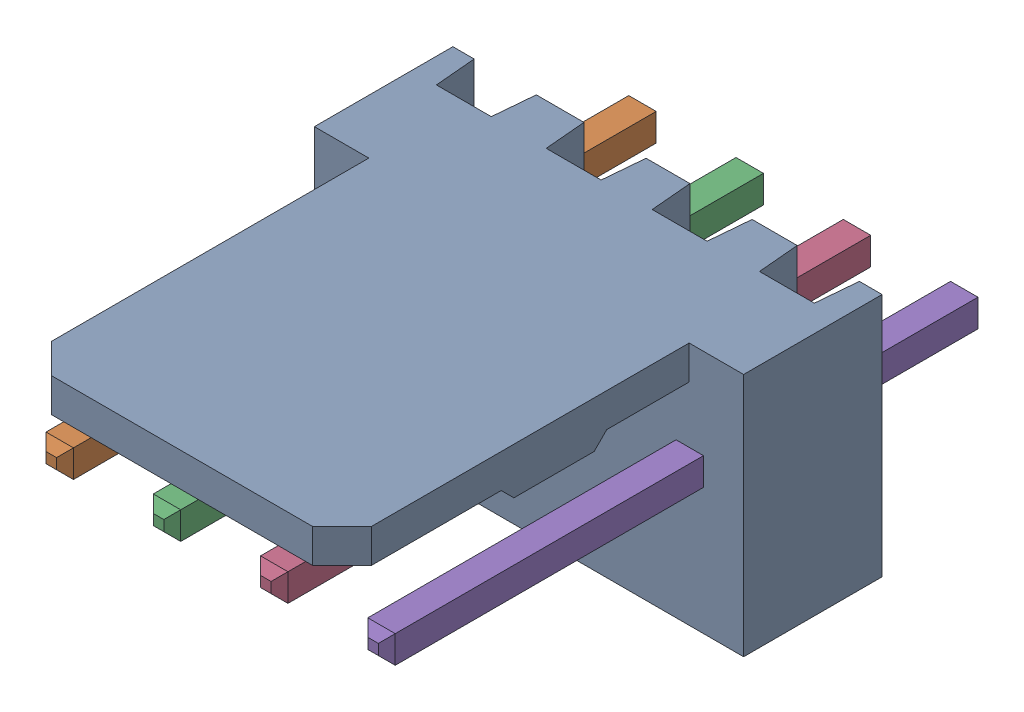
SolidWorks assembly Molex PCB 4 pin v3_4, configuration Default. Lengths in mm.
Overall size (10.16 5.79 14.92).
5 component instances, 2 part files, 0 mates.
Components (placement in the parent):
- BASE9710016 (2)-1: BASE9710016 (2) [Default] at (2.54 2.895 -8.22) size (10.16 5.79 11.5)
- PINO9710016 (2)-1: PINO9710016 (2) [Default] at (1.27 3.325 -0.72) size (0.65 0.65 14.2)
- PINO9710016 (2)-2: PINO9710016 (2) [Default] at (3.81 3.325 -0.72) size (0.65 0.65 14.2)
- PINO9710016 (2)-3: PINO9710016 (2) [Default] at (6.35 3.325 -0.72) size (0.65 0.65 14.2)
- PINO9710016 (2)-4: PINO9710016 (2) [Default] at (8.89 3.325 -0.72) size (0.65 0.65 14.2)
